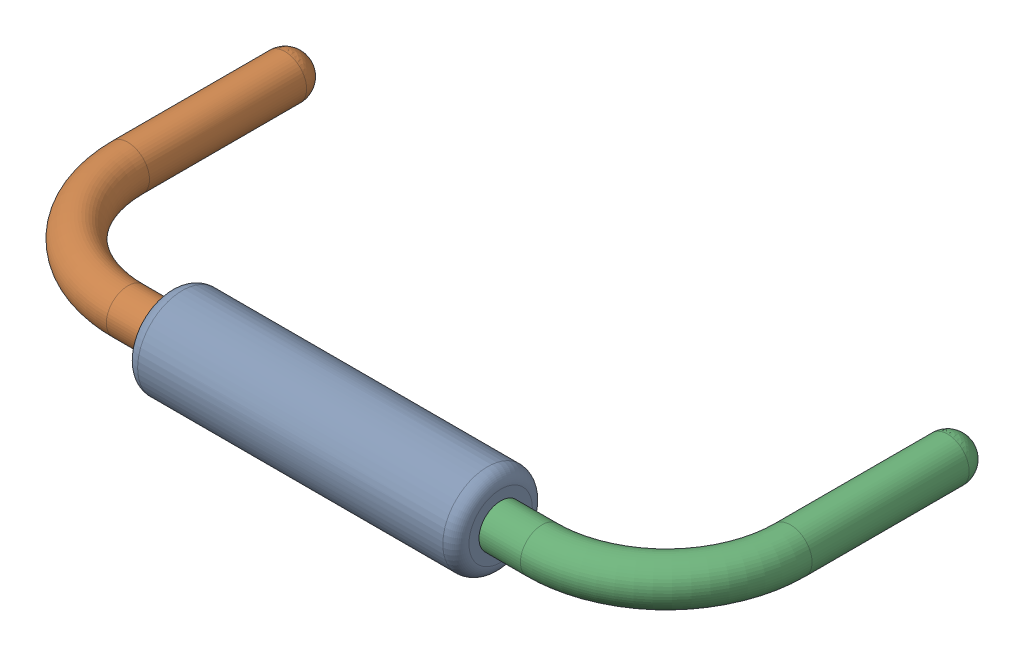
SolidWorks assembly R3, configuration Défaut. Lengths in mm.
Overall size (10.82 1.37 5.33).
4 component instances, 3 part files, 0 mates.
Components (placement in the parent):
- Open CASCADE STEP translator 6.8 1.10.1-1: Open CASCADE STEP translator 6.8 1.10.1 [Défaut] at origin size (10.82 1.37 5.33)
  - Body_1_7-1: Body_1_7 [Défaut] at origin size (5.08 1.37 1.37)
  - Pin_1_4-1: Pin_1_4 [Défaut] at origin size (3.2 0.66 4.98)
  - Pin_2_4-1: Pin_2_4 [Défaut] at (20.32 0 0) x (-1 0 0) z (0 0 1) size (3.2 0.66 4.98)
